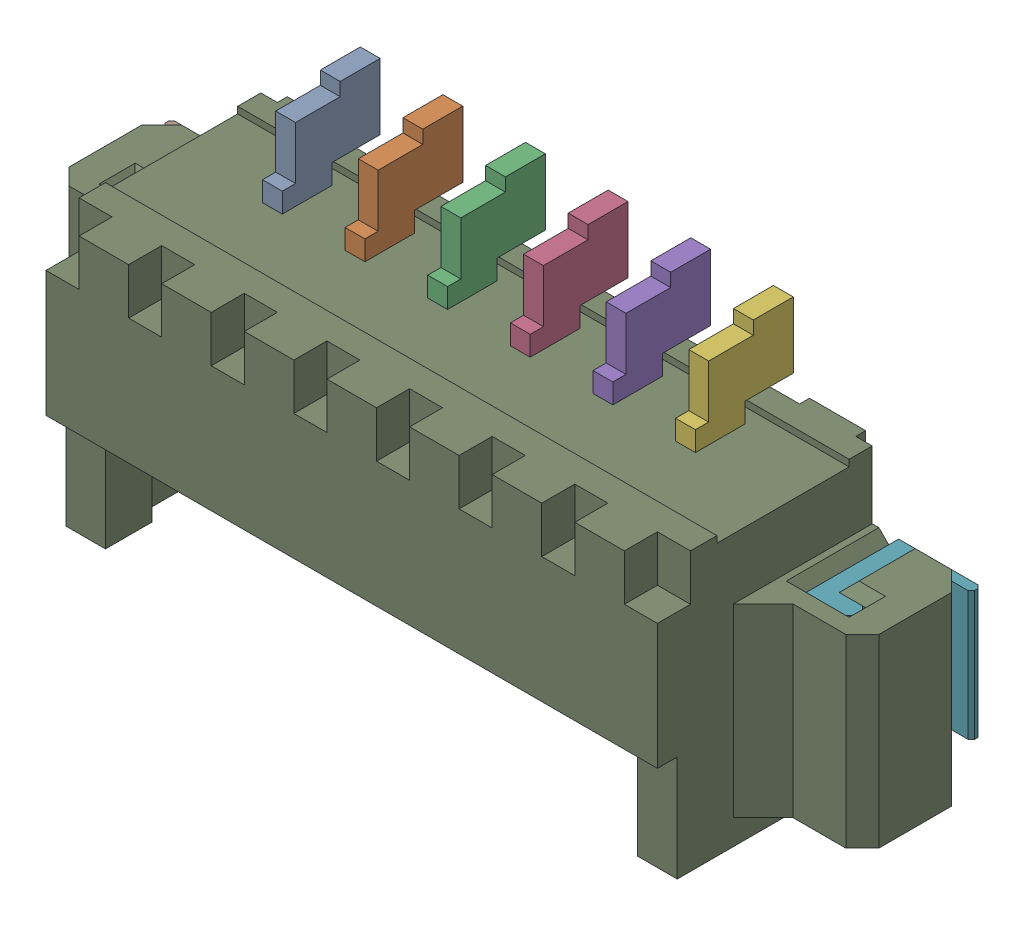
SolidWorks assembly 653106131822, configuration Default. Lengths in mm.
Overall size (12.25 5.4 3.41).
9 component instances, 3 part files, 0 mates.
Components (placement in the parent):
- 6531xx131822_PIN-1: 6531xx131822_PIN [Default] at (-3.125 2.7 -0.425) x (1 0 0) z (0 -1 0) size (0.3 1.48 4.54)
- 6531xx131822_PIN-2: 6531xx131822_PIN [Default] at (-1.875 2.7 -0.425) x (1 0 0) z (0 -1 0) size (0.3 1.48 4.54)
- 6531xx131822_PIN-3: 6531xx131822_PIN [Default] at (-0.625 2.7 -0.425) x (1 0 0) z (0 -1 0) size (0.3 1.48 4.54)
- 6531xx131822_PIN-4: 6531xx131822_PIN [Default] at (0.625 2.7 -0.425) x (1 0 0) z (0 -1 0) size (0.3 1.48 4.54)
- 6531xx131822_PIN-5: 6531xx131822_PIN [Default] at (1.875 2.7 -0.425) x (1 0 0) z (0 -1 0) size (0.3 1.48 4.54)
- 6531xx131822_PIN-6: 6531xx131822_PIN [Default] at (3.125 2.7 -0.425) x (1 0 0) z (0 -1 0) size (0.3 1.48 4.54)
- 6531xx131822_PIN_FLANGE-1: 6531xx131822_PIN_FLANGE [Default] at (5 -0.045 -1.05) size (1.25 1.95 1.4)
- 6531xx131822_PIN_FLANGE-2: 6531xx131822_PIN_FLANGE [Default] at (-5 -0.045 -1.05) x (-1 0 0) z (0 0 1) size (1.25 1.95 1.4)
- 653106131822-1: 653106131822 [Default] at origin size (12.25 4.2 3.4)
